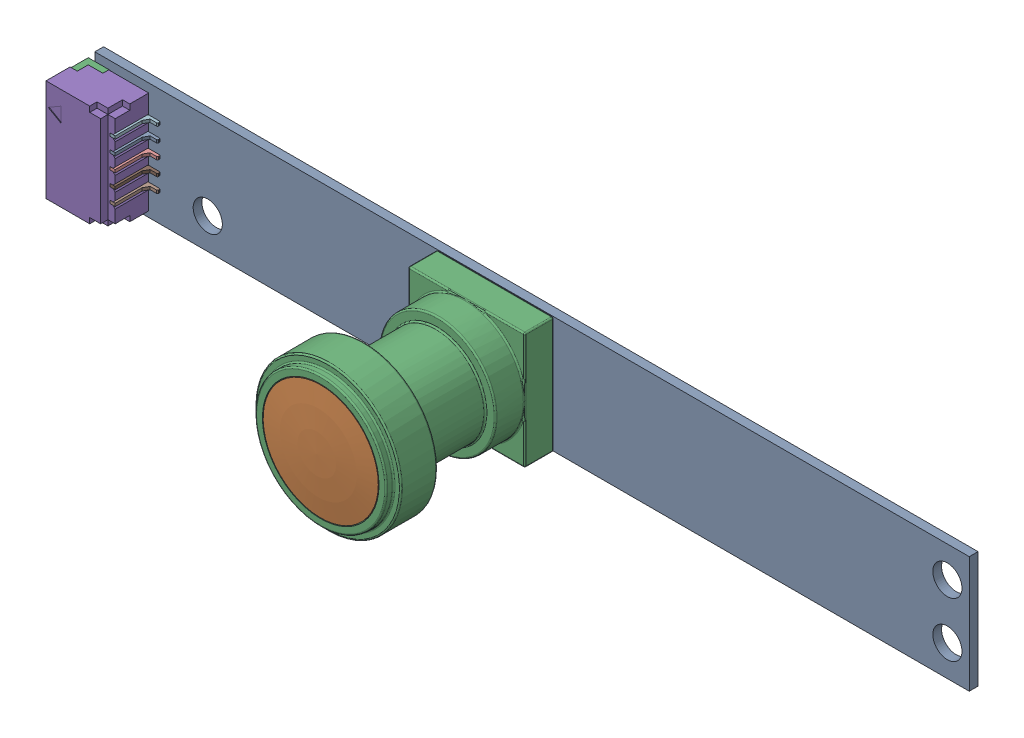
SolidWorks assembly Videw_JDEPC-OV04(170_FOV_lens), configuration Default. Lengths in mm.
Overall size (60.45 10 12.9).
3 component instances, 3 part files, 0 mates.
Components (placement in the parent):
- Videw_JDEPC-OV04-1: Videw_JDEPC-OV04 [Default] at origin size (60 8 0.6)
- SM05B-SRSS-TB-1: SM05B-SRSS-TB [Default] at (-23.7 0 0.6) x (0 -1 0) z (-1 0 0) size (7 2.9 4.95)
- 170_FOV_lens-1: 170_FOV_lens [Default] at (0 0 0.6) size (10 10 12.3)
